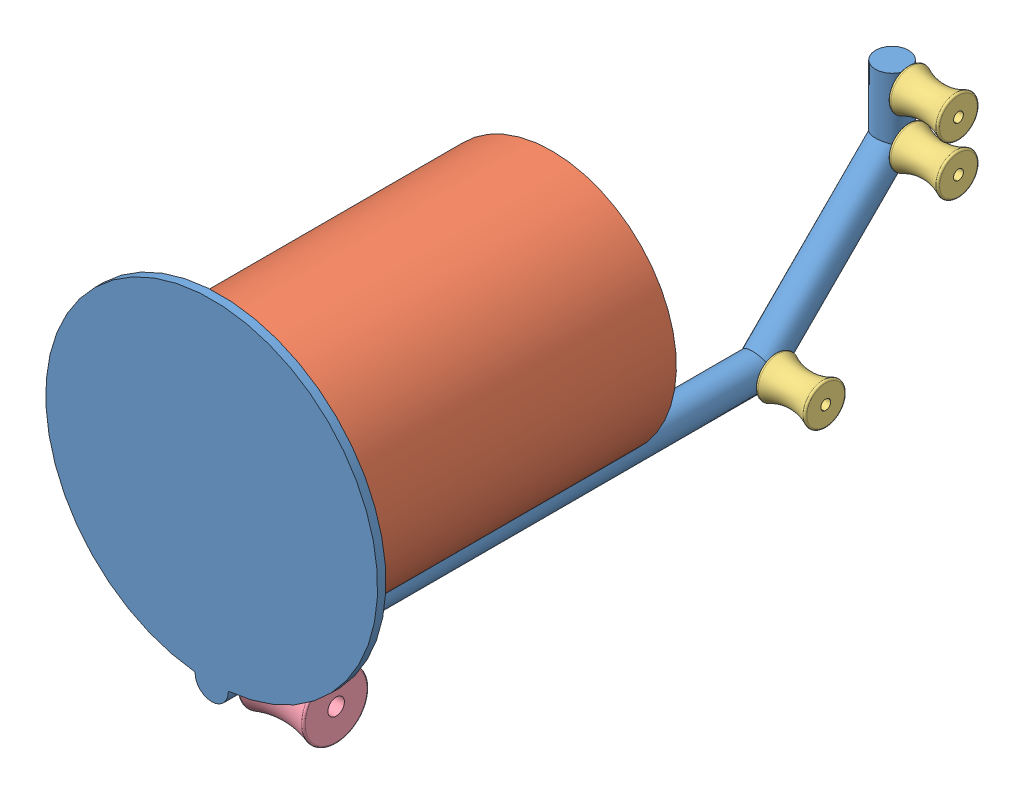
SolidWorks assembly Assemblage incubateur, configuration Défaut. Lengths in mm.
Overall size (200 226.45 428.69).
6 component instances, 4 part files, 15 mates.
Components (placement in the parent):
- Support métal-1: Support métal [Défaut] at (-15.5617 21.1278 145) size (200 210 420)
- incubateur-1: incubateur [Défaut] at (-15.5617 21.1278 145) x (0.328787 0.944404 0) z (0 0 -1) size (150 150 200)
- roulement-4: roulement [Défaut] at (-5.5617 31.1278 -260) x (0 -0.583344 0.812225) z (0 0.812225 0.583344) size (24.7 30 24.7)
- roulement-5: roulement [Défaut] at (-5.5617 1.1278 -260) x (0 -1 0) z (0 0 1) size (24.7 30 24.7)
- roulement-6: roulement [Défaut] at (-5.5617 -78.8722 -180) x (0 -1 0) z (0 0 1) size (24.7 30 24.7)
- roulement2-4: roulement2 [Défaut] at (34.4383 -78.8722 125) x (0 0.885434 0.464764) z (0 -0.464764 0.885434) size (39.18 40 39.18)
Mates (geometry in assembly coordinates):
- Coaxiale1: concentric anti-aligned: cylinder of Support métal-1 through (-34.047 31.9856 -240) axis (1 0 0) radius 3; cylinder of roulement-1 through (-5.5617 31.9856 -240) axis (-1 0 0) radius 3
- Coaxiale3: concentric anti-aligned: cylinder of Support métal-1 through (-34.047 -3.0144 -240) axis (1 0 0) radius 3; cylinder of roulement-2 through (-5.5617 -3.0144 -240) axis (-1 0 0) radius 3
- Coïncidente2: coincident anti-aligned: plane of Support métal-1 through (-5.5617 -53.2026 150) normal (1 0 0); plane of roulement-2 through (-5.5617 -6.5003 -243.5844) normal (-1 0 0)
- Coïncidente3: coincident anti-aligned: plane of Support métal-1 through (-5.5617 -53.2026 150) normal (1 0 0); plane of roulement-1 through (-5.5617 36.9544 -240.5584) normal (-1 0 0)
- Coïncidente4: coincident anti-aligned: plane of Support métal-1 through (-5.5617 -53.2026 150) normal (1 0 0); plane of roulement-3 through (-5.5617 213.0588 -32.8763) normal (-1 0 0)
- Coïncidente5: coincident anti-aligned: plane of Support métal-1 through (-15.5617 21.1278 145) normal (0 0 -1); plane of incubateur-1 through (-15.5617 21.1278 145) normal (0 0 1)
- Coaxiale4: concentric anti-aligned: cylinder of Support métal-1 through (-15.5617 21.1278 150) axis (0 0 -1) radius 100; cylinder of incubateur-1 through (-15.5617 21.1278 -55) axis (0 0 1) radius 75
- Coaxiale5: concentric aligned: cylinder of Support métal-1 through (-5.5617 -78.8722 -180) axis (-1 0 0) radius 3; cylinder of roulement-6 through (-5.5617 -78.8722 -180) axis (-1 0 0) radius 3
- Coaxiale6: concentric aligned: cylinder of Support métal-1 through (-5.5617 1.1278 -260) axis (-1 0 0) radius 3; cylinder of roulement-5 through (-5.5617 1.1278 -260) axis (-1 0 0) radius 3
- Coaxiale7: concentric anti-aligned: cylinder of Support métal-1 through (-5.5617 -78.8722 125) axis (-1 0 0) radius 3; cylinder of roulement2-4 through (34.4383 -78.8722 125) axis (1 0 0) radius 3
- Tangent1: tangent anti-aligned: cylinder of Support métal-1 through (-15.5617 -78.8722 -189.2127) axis (0 0 1) radius 10; plane of roulement2-4 through (-5.5617 -81.5285 123.6057) normal (-1 0 0)
- Tangent2: tangent anti-aligned: cylinder of Support métal-1 through (-15.5617 -78.8722 -189.2127) axis (0 0 1) radius 10; plane of roulement-6 through (-5.5617 -75.8722 -180) normal (-1 0 0)
- Tangent3: tangent anti-aligned: cylinder of Support métal-1 through (-15.5617 7.6421 -266.5144) axis (0 -0.707107 0.707107) radius 10; plane of roulement-5 through (-5.5617 4.1278 -260) normal (-1 0 0)
- Coaxiale8: concentric: cylinder of Support métal-1 through (-5.5617 31.1278 -260) axis (-1 0 0) radius 3; cylinder of roulement-4 through (-5.5617 31.1278 -260) axis (-1 0 0) radius 3
- Tangent4: tangent anti-aligned: cylinder of Support métal-1 through (-15.5617 41.1278 -260) axis (0 -1 0) radius 10; plane of roulement-4 through (-5.5617 32.8778 -262.4367) normal (-1 0 0)
